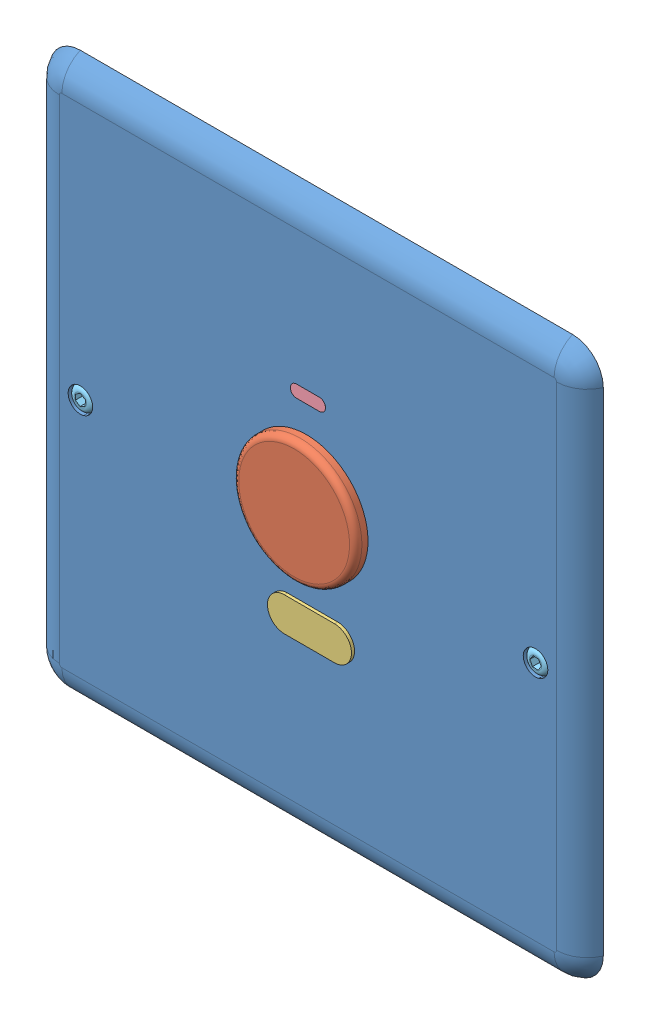
SolidWorks assembly OneLightAss, configuration Default. Lengths in mm.
Overall size (90 90 5).
6 component instances, 5 part files, 12 mates.
Components (placement in the parent):
- OneLight-1: OneLight [Default] at (35.1014 -9.0329 25.2598) size (90 90 3)
- Button20mm-1: Button20mm [Default] at (-22.4831 -10.332 25.2598) x (-0.918551 0.395303 0) z (0 0 1) size (20 20 5)
- CoverFilter-1: CoverFilter [Default] at (27.104 -36.1339 28.2598) size (13.66 5.5 0.5)
- LEDindicator-1: LEDindicator [Default] at (9.0642 5.258 25.2598) size (5.72 2 3)
- Screw4mm-1: Screw4mm [Default] at (-56.5846 -31.3747 28.2598) x (-0.887987 -0.459868 0) z (0 0 -1) size (4 4 3)
- Screw4mm-2: Screw4mm [Default] at (16.2053 -29.1954 28.2598) x (-0.998803 0.048907 0) z (0 0 -1) size (4 4 3)
Mates (geometry in assembly coordinates):
- Concentric3: concentric anti-aligned: cylinder of OneLight-1 through (-16.3905 -24.578 25.2598) axis (0 0 1) radius 10; cylinder of Button20mm-1 through (-16.3905 -24.578 30.2598) axis (0 0 -1) radius 10
- Coincident2: coincident: plane of OneLight-1 through (35.1014 -9.0329 28.2598) normal (0 0 1); plane of CoverFilter-1 through (-19.4821 -41.1616 28.2598) normal (0 0 -1)
- Concentric5: concentric: circle of OneLight-1; circle of CoverFilter-1
- Concentric6: concentric aligned: cylinder of OneLight-1 through (20.8398 -28.0843 25.2598) axis (0 0 1) radius 2; cylinder of Screw4mm-2 through (20.8398 -28.0843 25.2598) axis (0 0 1) radius 2
- Coincident3: coincident aligned: circle of OneLight-1; cylinder of Screw4mm-1 through (-53.1369 -28.0843 25.2598) axis (0 0 1) radius 2
- Coincident4: coincident anti-aligned: plane of OneLight-1 through (-18.0122 -8.2616 25.2598) normal (0 -1 0); plane of LEDindicator-1 through (-18.0122 -8.2616 28.2598) normal (0 1 0)
- Concentric8: concentric anti-aligned: cylinder of OneLight-1 through (-14.296 -9.2616 25.2598) axis (0 0 1) radius 1; cylinder of LEDindicator-1 through (-14.296 -9.2616 28.2598) axis (0 0 -1) radius 1
- Coincident5: coincident anti-aligned: circle of OneLight-1; circle of Screw4mm-1
- Coincident6: coincident anti-aligned: circle of OneLight-1; circle of Screw4mm-2
- Coincident7: coincident aligned: circle of OneLight-1; circle of Button20mm-1
- Coincident8: coincident aligned: line of OneLight-1 through (-14.296 -8.2616 25.2598) axis (-1 0 0); line of LEDindicator-1 through (-14.296 -8.2616 25.2598) axis (-1 0 0)
- Parallel1: parallel aligned: line of OneLight-1 through (-12.8952 -38.6616 28.2598) axis (-1 0 0); line of CoverFilter-1 through (-11.3268 -38.4116 28.2598) axis (-1 0 0)
